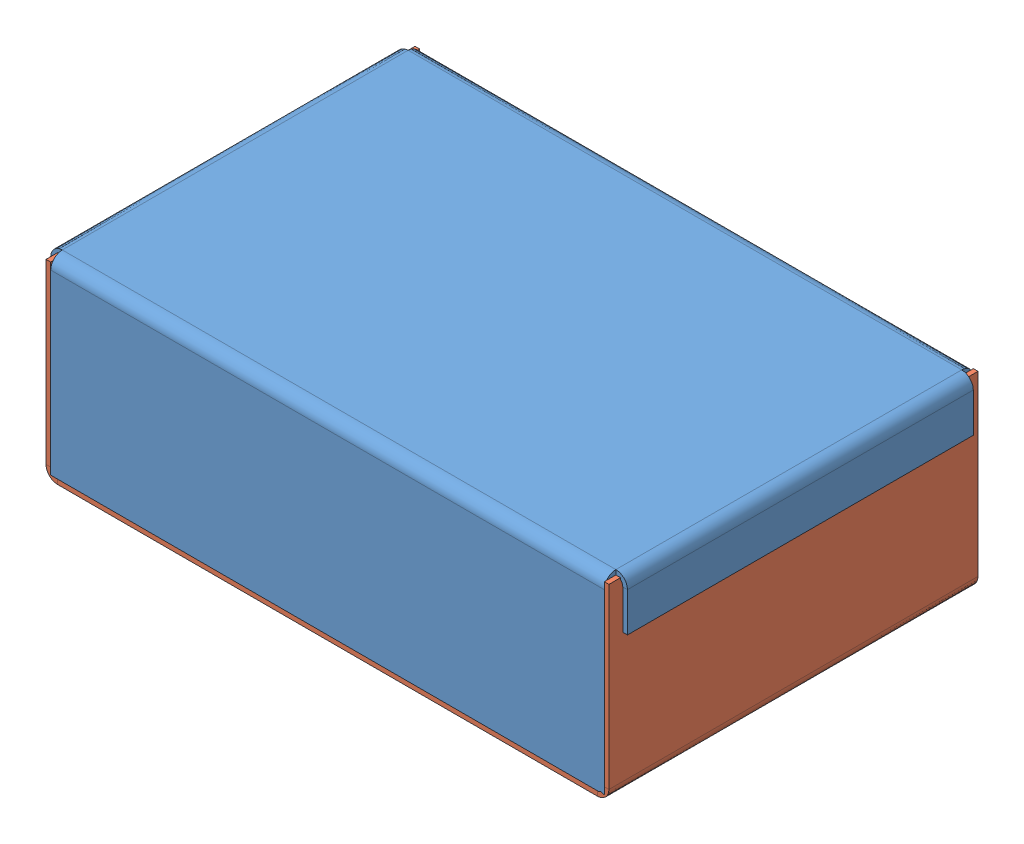
SolidWorks assembly Assem1, configuration Default. Lengths in mm.
Overall size (158.79 53.38 101.6).
2 component instances, 2 part files, 6 mates.
Components (placement in the parent):
- A SIDE-1: A SIDE [Default] at (0 0 -50.8) size (158.79 52.09 101.6)
- B SIDE-1: B SIDE [Default] at (0 -53.3806 -50.8) x (1 0 0) z (0 -1 0) size (154.98 101.6 52.09)
Mates (geometry in assembly coordinates):
- Coincident1: coincident aligned: plane of A SIDE-1 through (0 0 -50.8) normal (1 0 0); plane of assembly through (0 0 0) normal (1 0 0)
- Coincident2: coincident aligned: plane of A SIDE-1 through (0 0 0) normal (0 0 1); plane of assembly through (0 0 0) normal (0 0 1)
- Coincident3: coincident aligned: plane of A SIDE-1 through (0 0 -50.8) normal (0 1 0); plane of assembly through (0 0 0) normal (0 1 0)
- Coincident4: coincident: plane of A SIDE-1 through (0 0 0) normal (0 0 1); plane of B SIDE-1 through (-66.8935 -52.0903 0) normal (0 0 1)
- Coincident5: coincident: plane of A SIDE-1 through (0 -1.2903 -50.8) normal (0 -1 0); plane of B SIDE-1 through (86.7968 -1.2903 -101.6) normal (0 1 0)
- Coincident8: coincident anti-aligned: plane of A SIDE-1 through (76.2 -52.0903 -101.6) normal (1 0 0); plane of B SIDE-1 through (76.2 -53.3806 -50.8) normal (-1 0 0)
